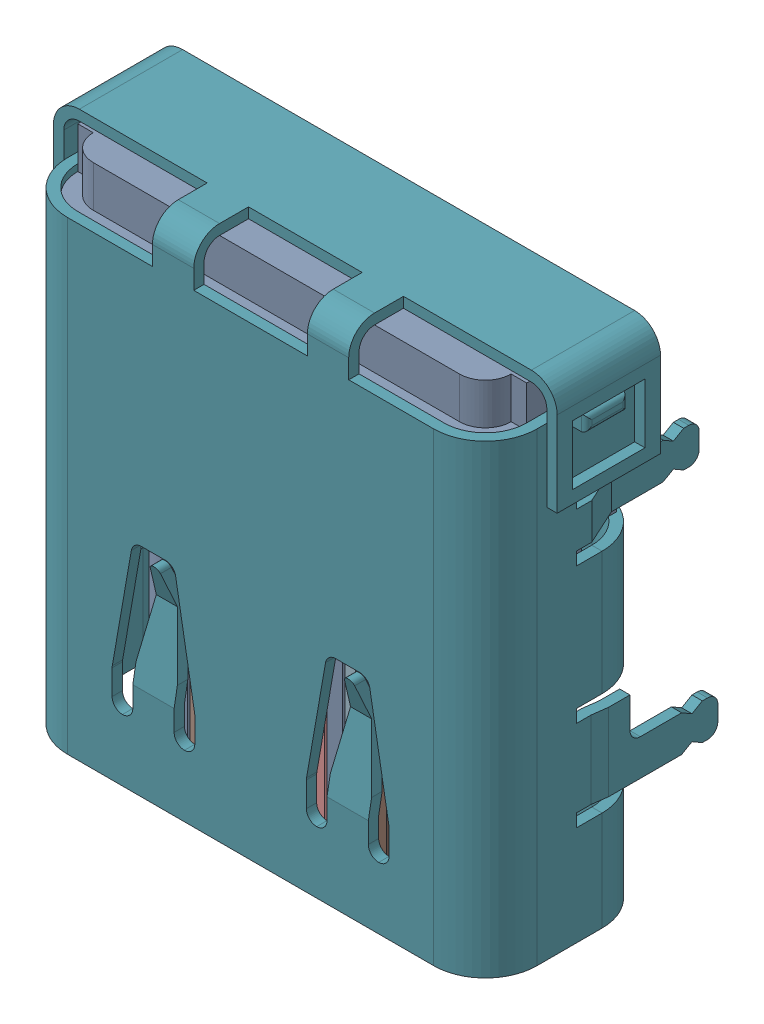
SolidWorks assembly 3D_PCB1_2021-12-30.step, configuration Défaut. Lengths in mm.
Overall size (9.75 9.87 4.46).
2 component instances, 1 part files, 0 mates.
Components (placement in the parent):
- e9773ad0a1ba4615a8cdbe787346df90.step-1: e9773ad0a1ba4615a8cdbe787346df90.step [Défaut] at (5.0419 -6.8961 1.6) size (9.75 9.87 4.46)
  - COMPOUND.step_810-1: COMPOUND.step_810 [Défaut] at origin size (9.75 9.87 4.46)
